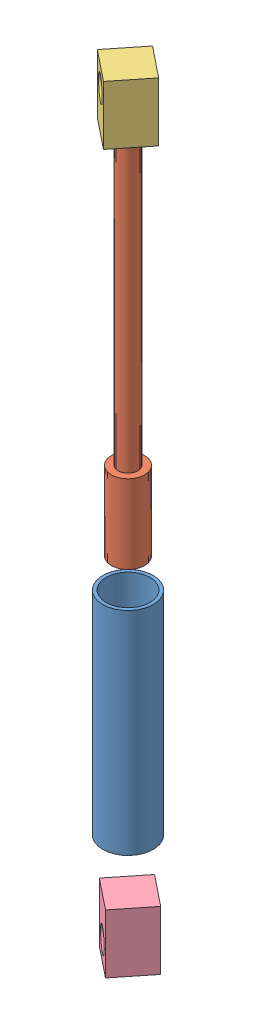
SolidWorks assembly Assem1, configuration Default. Lengths in mm.
Overall size (29.12 394.76 28.13).
4 component instances, 4 part files, 4 mates.
Components (placement in the parent):
- Cylinder-2: Cylinder [Default] at (122.8136 -109.9672 94.512) size (25.7 108 25.7)
- Piston-2: Piston [Default] at (122.8136 7.0244 94.512) size (17.05 195 17.05)
- upperconnector-1: upperconnector [Default] at (122.8136 194.0244 94.512) x (0.7811 0 0.624406) z (-0.624406 0 0.7811) size (20 30 20)
- lowerconnector-2: lowerconnector [Default] at (123.8241 -140.7371 94.4944) x (-0.7811 0 -0.624406) z (-0.624406 0 0.7811) size (20 30 20)
Mates (geometry in assembly coordinates):
- Concentric1: concentric aligned: cylinder of Cylinder-2 through (122.8136 -7.9672 94.512) axis (0 -1 0) radius 11.15; cylinder of Piston-2 through (122.8136 47.0244 94.512) axis (0 -1 0) radius 8.525
- Coincident1: coincident aligned: cylinder of Piston-2 through (122.8136 202.0244 94.512) axis (0 -1 0) radius 5; circle of upperconnector-1
- Coincident2: coincident anti-aligned: plane of Piston-2 through (122.8136 202.0244 94.512) normal (0 1 0); plane of upperconnector-1 through (122.8136 202.0244 94.512) normal (0 -1 0)
- Parallel4: parallel anti-aligned: line of upperconnector-1 through (124.3805 194.0244 108.5671) axis (0.624406 0 -0.7811); line of lowerconnector-2 through (137.8791 -170.7371 92.9274) axis (-0.624406 0 0.7811)
